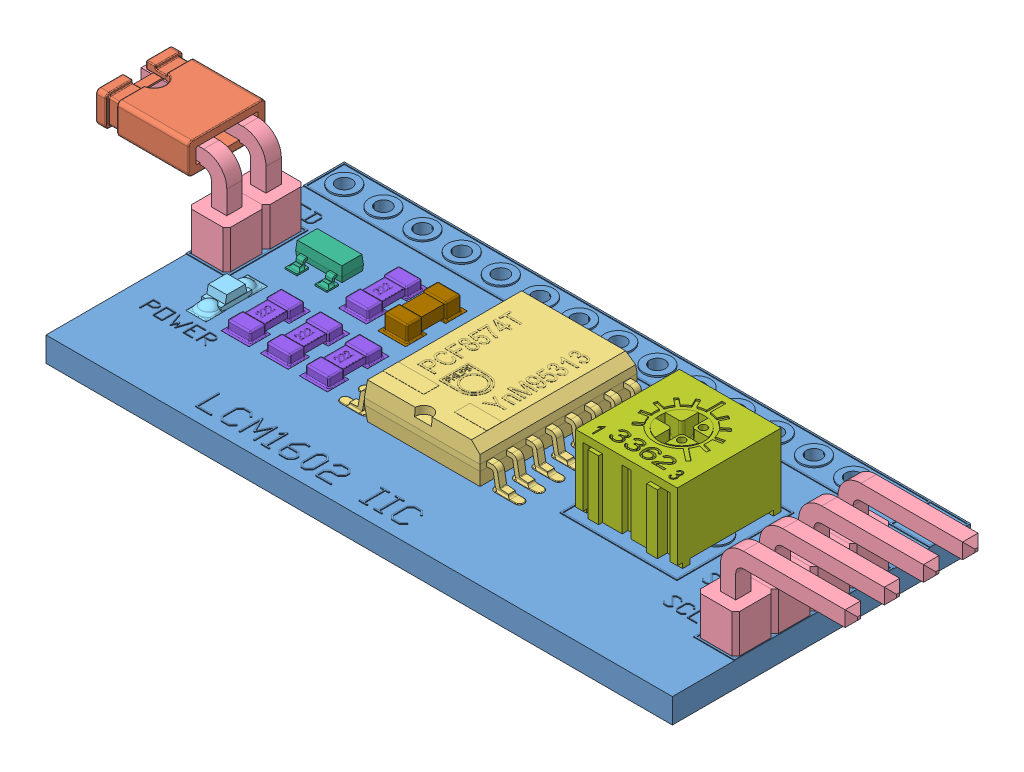
SolidWorks assembly i2c board, configuration Default. Lengths in mm.
Overall size (54.1 8.62 19.35).
17 component instances, 9 part files, 38 mates.
Components (placement in the parent):
- i2C board-1: i2C board [Default] at origin size (40.64 1.8 19.35)
- jumper__-1: jumper__ [Default] at (-0.2258 6.825 6.38) x (0 0 -1) z (0 1 0) size (5 6 2)
- pcf8574p-1: pcf8574p [Default] at (17.78 1.6 7.62) size (11.9 2.51 10.2)
- bent header-1: bent header [Default] at (38.1 1.7 5.08) x (0 0 1) z (-1 0 0) size (2.54 8 9.27)
- led-1: led [Default] at (2.54 1.6 10.16) x (0 0 -1) z (1 0 0) size (4 0.86 1.35)
- ssot3-1: ssot3 [Default] at (4.1275 1.6 5.08) size (3 1.13 3.09)
- trimpot 3662-1: trimpot 3662 [Default] at (29.21 1.6 7.62) size (6.6 6.67 6.99)
- smt_resistor222-2: smt_resistor222 [Default] at (10.16 1.6 10.16) size (1.8 0.6 4)
- smt_resistor222-3: smt_resistor222 [Default] at (7.62 1.6 10.16) size (1.8 0.6 4)
- smt_resistor222-4: smt_resistor222 [Default] at (5.08 1.6 10.16) size (1.8 0.6 4)
- smt_resistor222-5: smt_resistor222 [Default] at (7.62 1.6 5.08) size (1.8 0.6 4)
- bent header-3: bent header [Default] at (0 1.7 5.08) x (0 0 -1) z (1 0 0) size (2.54 8 9.27)
- bent header-4: bent header [Default] at (0 1.7 7.62) x (0 0 -1) z (1 0 0) size (2.54 8 9.27)
- bent header-5: bent header [Default] at (38.1 1.7 7.62) x (0 0 1) z (-1 0 0) size (2.54 8 9.27)
- bent header-6: bent header [Default] at (38.1 1.7 10.16) x (0 0 1) z (-1 0 0) size (2.54 8 9.27)
- bent header-7: bent header [Default] at (38.1 1.7 12.7) x (0 0 1) z (-1 0 0) size (2.54 8 9.27)
- smt_cap-2: smt_cap [Default] at (10.16 1.6 5.08) x (-1 0 0) z (0 0 -1) size (1.8 1 4)
Mates (geometry in assembly coordinates):
- Coincident2: coincident anti-aligned: plane of i2C board-1 through (0 1.6 0) normal (0 1 0); plane of trimpot 3662-1 through (29.21 1.6 7.62) normal (0 -1 0)
- Concentric3: concentric anti-aligned: cylinder of i2C board-1 through (29.21 1.6 5.08) axis (0 -1 0) radius 0.5; cylinder of trimpot 3662-1 through (29.21 -0.37 5.08) axis (0 1 0) radius 0.25
- Concentric4: concentric anti-aligned: cylinder of i2C board-1 through (31.75 1.6 7.62) axis (0 -1 0) radius 0.5; cylinder of trimpot 3662-1 through (31.75 -0.37 7.62) axis (0 1 0) radius 0.25
- Coincident3: coincident anti-aligned: plane of i2C board-1 through (0 1.6 0) normal (0 1 0); plane of pcf8574p-1 through (13.43 1.6 12.065) normal (0 -1 0)
- Coincident4: coincident anti-aligned: plane of i2C board-1 through (0 1.6 0) normal (0 1 0); plane of led-1 through (2.54 1.6 11.16) normal (0 -1 0)
- Coincident7: coincident anti-aligned: plane of i2C board-1 through (0 1.6 0) normal (0 1 0); plane of ssot3-1 through (4.1275 1.6 5.08) normal (0 -1 0)
- Concentric5: concentric anti-aligned: cylinder of i2C board-1 through (38.1 0 5.08) axis (0 1 0) radius 0.5; line of bent header-1 through (38.1 7.6 5.08) axis (0 -1 0)
- Coincident17: coincident aligned: plane of i2C board-1 through (0 1.6 0) normal (0 1 0); plane of smt_resistor222-5 through (7.62 1.6 5.08) normal (0 1 0)
- Coincident18: coincident aligned: plane of i2C board-1 through (0 1.6 0) normal (0 1 0); plane of smt_resistor222-2 through (10.16 1.6 10.16) normal (0 1 0)
- Coincident19: coincident aligned: plane of i2C board-1 through (0 1.6 0) normal (0 1 0); plane of smt_resistor222-3 through (7.62 1.6 10.16) normal (0 1 0)
- Coincident20: coincident aligned: plane of i2C board-1 through (0 1.6 0) normal (0 1 0); plane of smt_resistor222-4 through (5.08 1.6 10.16) normal (0 1 0)
- Distance2: distance = 2.54 mm aligned: plane of smt_resistor222-2 through (10.16 1.6 10.16) normal (1 0 0); plane of smt_resistor222-3 through (7.62 1.6 10.16) normal (1 0 0)
- Distance3: distance = 2.54 mm aligned: plane of smt_resistor222-3 through (7.62 1.6 10.16) normal (1 0 0); plane of smt_resistor222-4 through (5.08 1.6 10.16) normal (1 0 0)
- Coincident23: coincident aligned: plane of smt_resistor222-2 through (10.16 1.6 10.16) normal (0 0 1); plane of smt_resistor222-3 through (7.62 1.6 10.16) normal (0 0 1)
- Coincident24: coincident aligned: plane of smt_resistor222-2 through (10.16 1.6 10.16) normal (0 0 1); plane of smt_resistor222-4 through (5.08 1.6 10.16) normal (0 0 1)
- Coincident27: coincident anti-aligned: plane of i2C board-1 through (0 1.7 0) normal (0 1 0); plane of bent header-1 through (38.1 1.7 5.08) normal (0 -1 0)
- Coincident28: coincident anti-aligned: plane of i2C board-1 through (0 1.7 0) normal (0 1 0); plane of bent header-3 through (0 1.7 5.08) normal (0 -1 0)
- Concentric7: concentric aligned: cylinder of i2C board-1 through (0 1.6 5.08) axis (0 -1 0) radius 0.5; line of bent header-3 through (0 7.6 5.08) axis (0 -1 0)
- Parallel1: parallel anti-aligned: plane of i2C board-1 through (0 0 0) normal (0 0 1); plane of bent header-3 through (-1.02 4.2 3.81) normal (0 0 -1)
- Parallel2: parallel aligned: plane of i2C board-1 through (0 0 0) normal (0 0 1); plane of bent header-1 through (39.12 4.2 6.35) normal (0 0 1)
- Concentric8: concentric aligned: cylinder of i2C board-1 through (0 1.6 7.62) axis (0 -1 0) radius 0.5; line of bent header-4 through (0 7.6 7.62) axis (0 -1 0)
- Coincident35: coincident anti-aligned: plane of i2C board-1 through (0 1.7 0) normal (0 1 0); plane of bent header-4 through (0 1.7 7.62) normal (0 -1 0)
- Distance4: distance = 0.2 mm anti-aligned: plane of jumper__-1 through (-7.2258 7.325 4.38) normal (0 0 1); plane of bent header-3 through (-1 5.7 4.58) normal (0 0 -1)
- Coincident37: coincident anti-aligned: plane of jumper__-1 through (-6.8258 7.2 8.38) normal (0 -1 0); plane of bent header-3 through (-1 7.2 5.58) normal (0 1 0)
- Distance5: distance = 10.16 mm aligned: plane of smt_resistor222-2 through (10.16 1.6 10.16) normal (1 0 0); plane of i2C board-1 through (0 0 0) normal (1 0 0)
- Coincident39: coincident anti-aligned: plane of led-1 through (2.54 1.6 10.16) normal (0 0 -1); plane of smt_resistor222-4 through (5.08 1.6 10.16) normal (0 0 1)
- Distance6: distance = 2.54 mm aligned: plane of led-1 through (2.54 1.6 10.16) normal (1 0 0); plane of smt_resistor222-4 through (5.08 1.6 10.16) normal (1 0 0)
- Coincident41: coincident aligned: plane of smt_resistor222-3 through (7.62 1.6 10.16) normal (1 0 0); plane of smt_resistor222-5 through (7.62 1.6 5.08) normal (1 0 0)
- Distance7: distance = 5.08 mm aligned: plane of smt_resistor222-5 through (7.62 1.6 5.08) normal (0 0 1); plane of smt_resistor222-3 through (7.62 1.6 10.16) normal (0 0 1)
- Coincident48: coincident anti-aligned: plane of smt_resistor222-2 through (10.16 1.6 10.16) normal (1 0 0); plane of smt_cap-2 through (10.16 1.6 5.08) normal (-1 0 0)
- Coincident49: coincident anti-aligned: plane of smt_resistor222-5 through (7.62 1.6 5.08) normal (0 0 1); plane of smt_cap-2 through (10.16 1.6 5.08) normal (0 0 -1)
- Coincident50: coincident aligned: plane of i2C board-1 through (0 1.6 0) normal (0 1 0); plane of smt_cap-2 through (10.16 1.6 5.08) normal (0 1 0)
- Distance10: distance = 5.08 mm anti-aligned: plane of smt_cap-2 through (10.16 1.6 5.08) normal (0 0 -1); plane of i2C board-1 through (0 0 0) normal (0 0 1)
- Distance11: distance = 5.08 mm aligned: plane of ssot3-1 through (5.08 1.6 5.08) normal (1 0 0); plane of i2C board-1 through (0 0 0) normal (1 0 0)
- Distance12: distance = 5.08 mm aligned: plane of ssot3-1 through (4.1275 1.6 5.08) normal (0 0 1); plane of i2C board-1 through (0 0 0) normal (0 0 1)
- Distance13: distance = 7.62 mm aligned: plane of pcf8574p-1 through (17.78 1.6 7.62) normal (0 0 1); plane of i2C board-1 through (0 0 0) normal (0 0 1)
- Distance14: distance = 17.78 mm aligned: plane of pcf8574p-1 through (17.78 1.6 7.62) normal (1 0 0); plane of i2C board-1 through (0 0 0) normal (1 0 0)
- Parallel3: parallel anti-aligned: plane of i2C board-1 through (0 0 0) normal (0 0 1); plane of bent header-4 through (-1 5.7 7.12) normal (0 0 -1)
